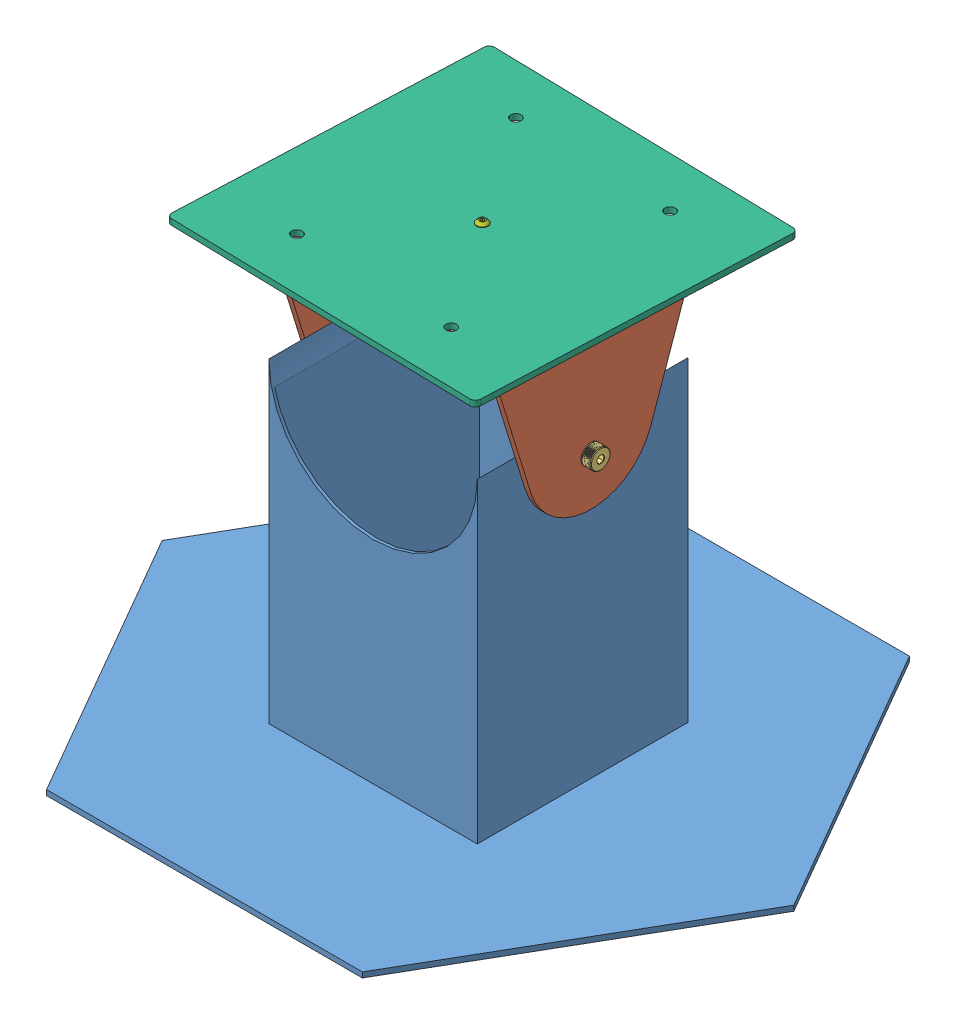
SolidWorks assembly FINAL, configuration Default. Lengths in mm.
Overall size (304.8 212.8 263.96).
10 component instances, 7 part files, 18 mates.
Components (placement in the parent):
- Bottom-1: Bottom [Default] at origin size (304.8 154.94 263.96)
- Top_Part-1: Top_Part [Default] at (0.6698 205.7295 -1.1534) x (-1 0 0) z (0 0.018164 0.999835) size (107.25 89.47 101.61)
- 91259A169_ALLOY STEEL SHOULDER SCREW-1: 91259A169_ALLOY STEEL SHOULDER SCREW [91259A169] at (59.051 142.24 0) x (0 0.955039 0.296479) z (1 0 0) size (9.53 9.53 18.09)
- 91259A169_ALLOY STEEL SHOULDER SCREW-2: 91259A169_ALLOY STEEL SHOULDER SCREW [91259A169] at (-57.7113 142.24 0) x (0 -0.544256 0.838919) z (-1 0 0) size (9.53 9.53 18.09)
- 90107A011_TYPE 316 STAINLESS STEEL FLAT WASHER-1: 90107A011_TYPE 316 STAINLESS STEEL FLAT WASHER [90107A011] at (48.2879 142.24 0) x (0 0 -1) z (0 -1 0) size (11.11 0.61 11.11)
- 90107A011_TYPE 316 STAINLESS STEEL FLAT WASHER-2: 90107A011_TYPE 316 STAINLESS STEEL FLAT WASHER [90107A011] at (-48.8975 142.24 0) x (0 1 0) z (0 0 -1) size (11.11 0.61 11.11)
- 90480A011_LOW-STRENGTH STEEL HEX NUT-1: 90480A011_LOW-STRENGTH STEEL HEX NUT [90480A011] at (-46.7004 143.609 -3.1282) x (0 0.736553 0.67638) z (0 0.67638 -0.736553) size (9.53 3.99 11)
- 90480A011_LOW-STRENGTH STEEL HEX NUT-2: 90480A011_LOW-STRENGTH STEEL HEX NUT [90480A011] at (46.1264 142.2519 0.796) x (0 0.061262 -0.998122) z (0 -0.998122 -0.061262) size (9.53 3.99 11)
- Top_Rotating-3: Top_Rotating [Default] at (0.6698 208.3859 -1.2017) x (-0.999735 -0.000418 -0.023016) z (0.023019 -0.018159 -0.99957) size (152.4 2.77 152.4)
- 92949A106_18-8 SS BUTTON-HEAD SOCKET CAP SCREW-3: 92949A106_18-8 SS BUTTON-HEAD SOCKET CAP SCREW [92949A106] at (0.6698 212.6499 -1.2791) x (0.175758 0.017881 0.984271) z (0 0.999835 -0.018164) size (5.41 5.41 8.16)
Mates (geometry in assembly coordinates):
- Coincident1: coincident: plane of Bottom-1 through (-50.292 154.94 -50.8) normal (-1 0 0); plane of Top_Part-1 through (-50.292 365.8566 -4.0624) normal (1 0 0)
- Parallel1: parallel: plane of Bottom-1 through (50.292 154.94 -50.8) normal (1 0 0); plane of Top_Part-1 through (51.6316 149.4017 -0.1301) normal (-1 0 0)
- Concentric1: concentric: cylinder of Bottom-1 through (-152.5645 142.24 0) axis (1 0 0) radius 3.175; cylinder of Top_Part-1 through (54.2952 142.24 0) axis (-1 0 0) radius 3.175
- Coincident4: coincident: plane of Top_Part-1 through (54.2885 149.4017 -0.1301) normal (1 0 0); plane of 91259A169_ALLOY STEEL SHOULDER SCREW-1 through (54.2885 143.652 -4.5484) normal (-1 0 0)
- Coincident5: coincident: cylinder of Bottom-1 through (-152.5645 142.24 0) axis (1 0 0) radius 3.175; circle of 91259A169_ALLOY STEEL SHOULDER SCREW-1
- Coincident6: coincident: plane of Top_Part-1 through (-52.9488 365.8566 -4.0624) normal (-1 0 0); plane of 91259A169_ALLOY STEEL SHOULDER SCREW-2 through (-52.9488 138.2446 -2.592) normal (1 0 0)
- Coincident7: coincident: circle of Top_Part-1; cylinder of 91259A169_ALLOY STEEL SHOULDER SCREW-2 through (-40.2488 142.24 0) axis (1 0 0) radius 3.175
- Coincident9: coincident: plane of Bottom-1 through (48.8975 -35.56 -49.4055) normal (-1 0 0); plane of 90107A011_TYPE 316 STAINLESS STEEL FLAT WASHER-1 through (48.8975 142.24 0) normal (1 0 0)
- Concentric3: concentric: cylinder of Bottom-1 through (-152.5645 142.24 0) axis (1 0 0) radius 3.175; cylinder of 90107A011_TYPE 316 STAINLESS STEEL FLAT WASHER-1 through (48.2879 142.24 0) axis (1 0 0) radius 2.5781
- Coincident10: coincident: plane of Bottom-1 through (-48.8975 -35.56 -49.4055) normal (1 0 0); plane of 90107A011_TYPE 316 STAINLESS STEEL FLAT WASHER-2 through (-48.8975 142.24 0) normal (-1 0 0)
- Concentric4: concentric: cylinder of Bottom-1 through (-152.5645 142.24 0) axis (1 0 0) radius 3.175; cylinder of 90107A011_TYPE 316 STAINLESS STEEL FLAT WASHER-2 through (-48.8975 142.24 0) axis (1 0 0) radius 2.5781
- Coincident14: coincident: plane of 90107A011_TYPE 316 STAINLESS STEEL FLAT WASHER-2 through (-48.2879 142.24 0) normal (1 0 0); plane of 90480A011_LOW-STRENGTH STEEL HEX NUT-1 through (-48.2879 138.2414 -4.3242) normal (-1 0 0)
- Tangent11: tangent: cylinder of 91259A169_ALLOY STEEL SHOULDER SCREW-2 through (-40.2488 142.24 0) axis (1 0 0) radius 1.6891; curve of 90480A011_LOW-STRENGTH STEEL HEX NUT-1
- Tangent17: tangent: cylinder of 90107A011_TYPE 316 STAINLESS STEEL FLAT WASHER-1 through (48.8975 142.24 0) axis (-1 0 0) radius 5.5563; plane of 90480A011_LOW-STRENGTH STEEL HEX NUT-2 through (47.7139 144.7047 5.718) normal (0 -0.061262 0.998122)
- Coincident28: coincident: plane of Top_Part-1 through (108.9151 208.3859 -1.2017) normal (0 0.999835 -0.018164); plane of Top_Rotating-3 through (72.6147 209.7543 74.122) normal (0 -0.999835 0.018164)
- Coincident29: coincident: circle of Top_Part-1; circle of Top_Rotating-3
- Coincident30: coincident: plane of Top_Rotating-3 through (72.6147 212.5199 74.0717) normal (0 0.999835 -0.018164); plane of 92949A106_18-8 SS BUTTON-HEAD SOCKET CAP SCREW-3 through (-1.9932 211.1602 -0.7765) normal (0 -0.999835 0.018164)
- Tangent21: tangent: cylinder of Top_Rotating-3 through (0.6698 211.1515 -1.2519) axis (0 -0.999835 0.018164) radius 1.4224; curve of 92949A106_18-8 SS BUTTON-HEAD SOCKET CAP SCREW-3
